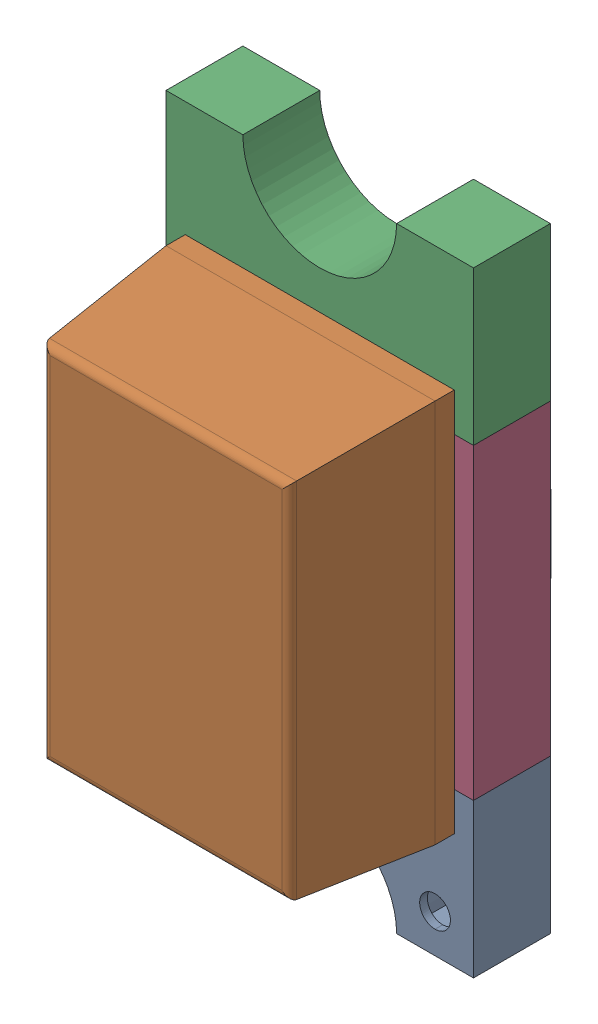
SolidWorks assembly LED2, configuration Défaut. Lengths in mm.
Overall size (0.8 1.6 0.6).
6 component instances, 5 part files, 0 mates.
Components (placement in the parent):
- User Library-LED_0603_R-1: User Library-LED_0603_R [Défaut] at (4.5466 -44.0054 0) x (0 1 0) z (0 0 1) size (1.6 0.8 0.6)
  - User Library-LED_0603_R_Pocket002-1: User Library-LED_0603_R_Pocket002 [Défaut] at origin size (0.4 0.8 0.2)
  - User Library-LED_0603_R_Pad004-1: User Library-LED_0603_R_Pad004 [Défaut] x (1 0 0) z (0 0 -1) size (0.4 0.8 0)
  - User Library-LED_0603_R_Fillet-1: User Library-LED_0603_R_Fillet [Défaut] at origin size (1 0.7 0.4)
  - User Library-LED_0603_R_Pocket001-1: User Library-LED_0603_R_Pocket001 [Défaut] at origin size (0.4 0.8 0.2)
  - User Library-LED_0603_R_Pad-1: User Library-LED_0603_R_Pad [Défaut] at origin size (0.8 0.8 0.2)
